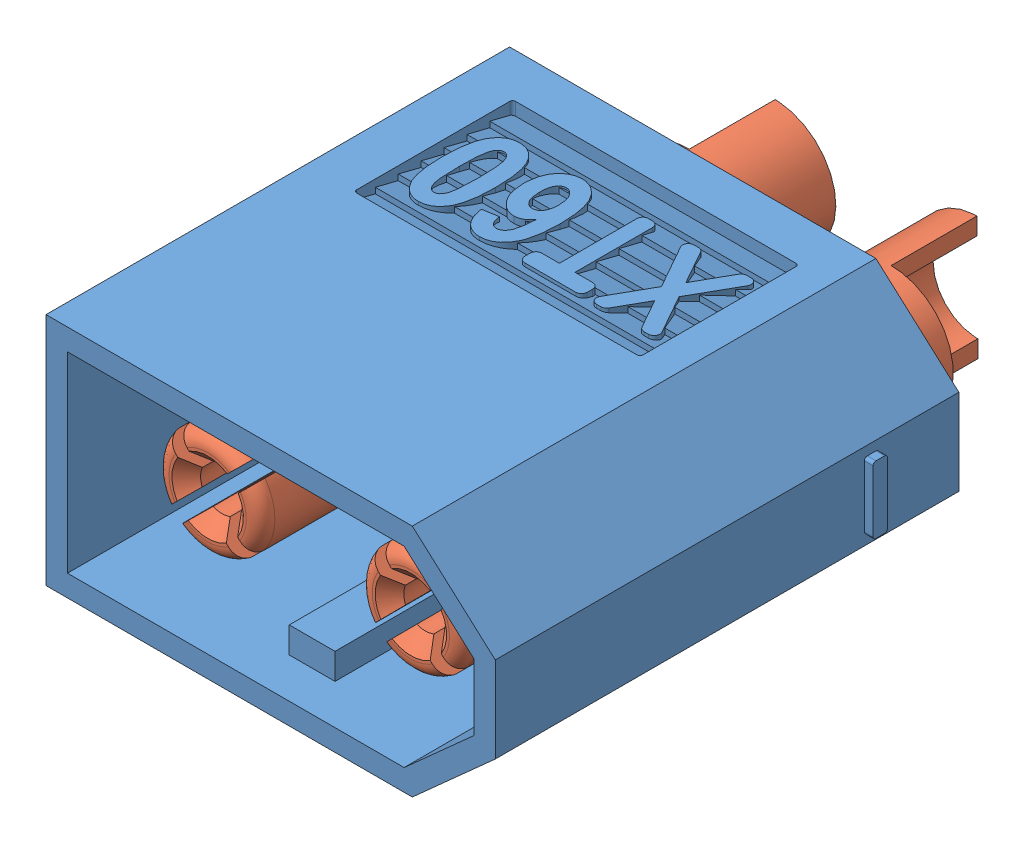
SolidWorks assembly XT-60_Macho 1, configuration Valor predeterminado. Lengths in mm.
Overall size (16.3 8.2 28.2).
3 component instances, 2 part files, 7 mates.
Components (placement in the parent):
- XT-60_Macho-1: XT-60_Macho [Valor predeterminado] at (-37.9952 28.536 -8.1) size (16.3 8.2 16.2)
- PinoXT-60_Macho-1: PinoXT-60_Macho [Valor predeterminado] at (-26.6452 32.636 -13.1) x (-0.008124 0.999967 0) z (0.999967 0.008124 0) size (4.3 26.83 4.3)
- PinoXT-60_Macho-2: PinoXT-60_Macho [Valor predeterminado] at (-33.7452 32.636 -13.1) x (-0.014321 -0.999897 0) z (-0.999897 0.014321 0) size (4.3 26.83 4.3)
Mates (geometry in assembly coordinates):
- Concêntrico1: concentric: cylinder of XT-60_Macho-1 through (-26.6452 32.636 8.1) axis (0 0 -1) radius 2.15; cylinder of PinoXT-60_Macho-1 through (-26.6452 32.636 -3.1) axis (0 0 -1) radius 2.15
- Concêntrico2: concentric: cylinder of XT-60_Macho-1 through (-33.7452 32.636 8.1) axis (0 0 -1) radius 2.15; cylinder of PinoXT-60_Macho-2 through (-33.7452 32.636 -3.1) axis (0 0 -1) radius 2.15
- Distância1: distance = 1.4 mm: plane of PinoXT-60_Macho-1 through (-26.6627 34.786 6.7) normal (0 0 1); plane of XT-60_Macho-1 through (-37.9952 28.536 8.1) normal (0 0 1)
- Distância2: distance = 1.4 mm: plane of PinoXT-60_Macho-2 through (-33.776 30.4863 6.7) normal (0 0 1); plane of XT-60_Macho-1 through (-37.9952 28.536 8.1) normal (0 0 1)
- LimitDistance1: limit distance = 0 mm: plane of ? through (-37.9952 38.536 8.1) normal (0 0 -1); plane of XT-60_Macho-1 through (-37.9952 28.536 8.1) normal (0 0 1)
- Width1: width: plane of XT-60_Macho-1 through (-23.0452 31.4709 -1.3) normal (-1 0 0); plane of XT-60_Macho-1 through (-37.2452 35.986 -1.3) normal (1 0 0); plane of ? through (-37.1952 29.336 0.4) normal (-1 0 0); plane of ? through (-23.0952 33.7788 0.4) normal (1 0 0)
- Width2: width: plane of ? through (-37.1952 35.936 0.4) normal (0 1 0); plane of ? through (-25.5014 29.336 0.4) normal (0 -1 0); plane of XT-60_Macho-1 through (-37.2452 29.286 -1.3) normal (0 1 0); plane of XT-60_Macho-1 through (-25.4822 35.986 -1.3) normal (0 -1 0)
